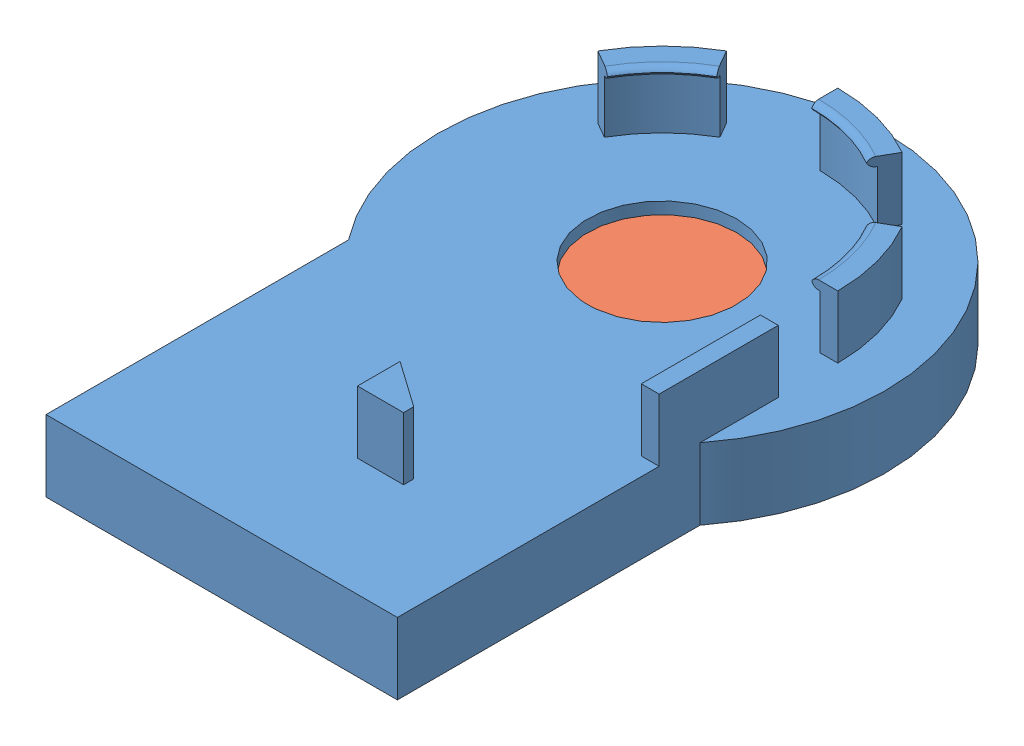
SolidWorks assembly WrenchHolderAssem, configuration Default. Lengths in mm.
Overall size (75 47.9 111.45).
2 component instances, 2 part files, 2 mates.
Components (placement in the parent):
- WrenchHolderV2-1: WrenchHolderV2 [Default] at (24.761 54.4131 71.1131) size (75 22.5 111.45)
- Electromagnet-1: Electromagnet [Default] at (24.761 54.4131 71.1131) x (0.998284 0 -0.058561) z (0.058561 0 0.998284) size (70 35.4 70)
Mates (geometry in assembly coordinates):
- Concentric1: concentric aligned: cylinder of WrenchHolderV2-1 through (24.761 64.4131 71.1131) axis (0 -1 0) radius 35.5; cylinder of Electromagnet-1 through (24.761 64.4131 71.1131) axis (0 -1 0) radius 35
- Coincident1: coincident anti-aligned: plane of WrenchHolderV2-1 through (24.761 64.4131 71.1131) normal (0 -1 0); plane of Electromagnet-1 through (24.761 64.4131 71.1131) normal (0 1 0)
